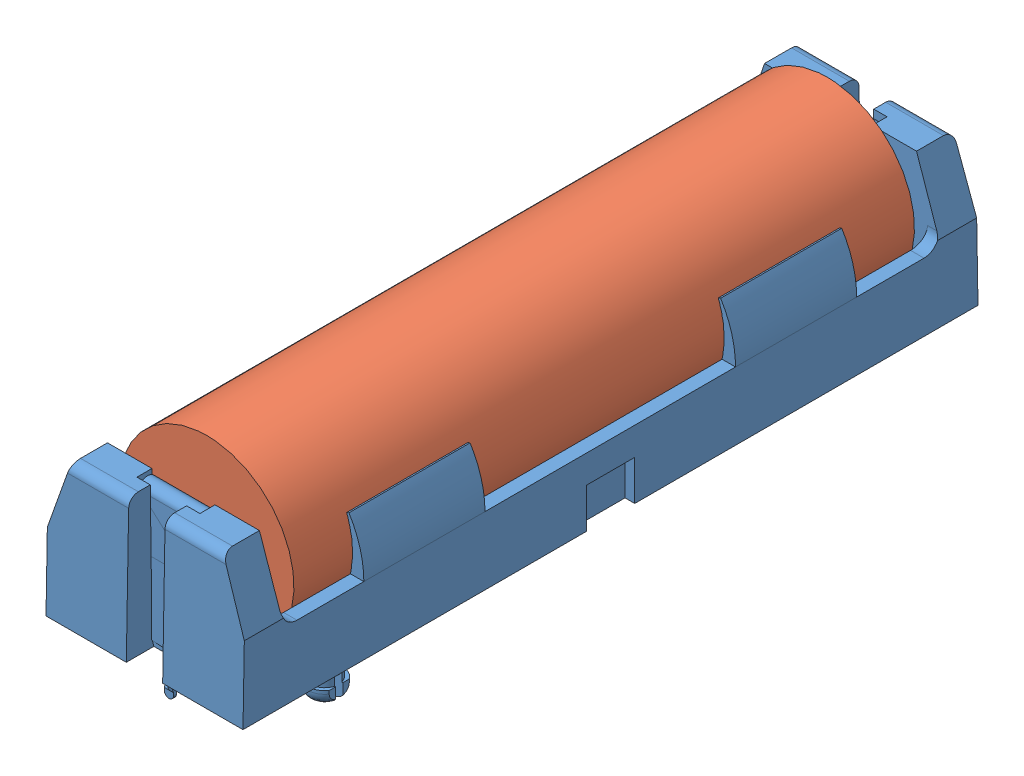
SolidWorks assembly Battery Assembly, configuration Default. Lengths in mm.
Overall size (20.65 21.9 77.14).
2 component instances, 2 part files, 2 mates.
Components (placement in the parent):
- Battery Holder - keystone-PN1043-1: Battery Holder - keystone-PN1043 [Default] at (27.979 42.1729 59.6018) size (20.65 18.93 77.14)
- battery_6612-1: battery_6612 [Default] at (36.333 41.1675 88.8909) x (1 0 0) z (0 1 0) size (18.3 65.05 18.3)
Mates (geometry in assembly coordinates):
- Concentric1: concentric: cylinder of Battery Holder - keystone-PN1043-1 through (36.333 41.1675 91.3285) axis (0 0 -1) radius 9.144; cylinder of battery_6612-1 through (36.333 41.1675 23.8409) axis (0 0 1) radius 9.15
- Coincident1: coincident anti-aligned: plane of Battery Holder - keystone-PN1043-1 through (33.158 41.8279 88.8909) normal (0 0 -1); plane of battery_6612-1 through (36.333 41.1675 88.8909) normal (0 0 1)
